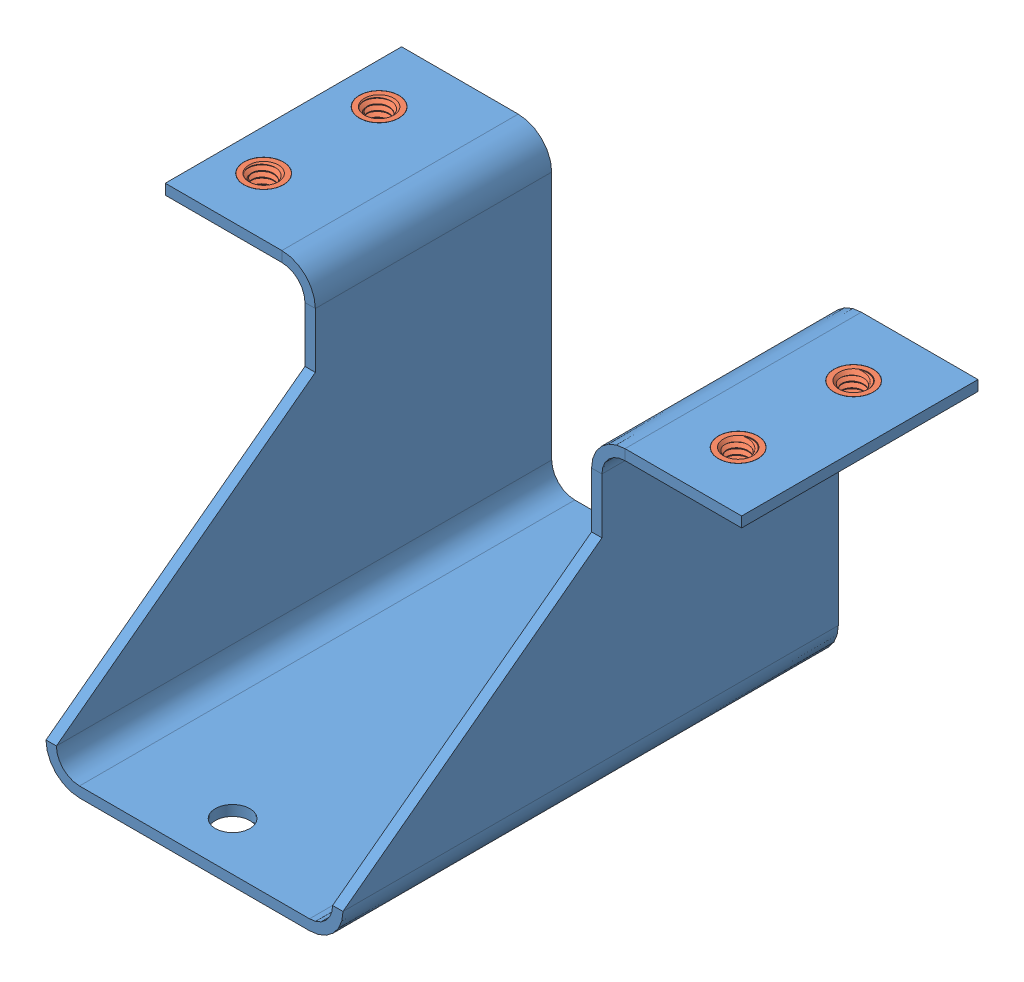
SolidWorks assembly Light Source Mount, configuration Default. Lengths in mm.
Overall size (126.81 70.06 108.97).
5 component instances, 2 part files, 4 mates.
Components (placement in the parent):
- Light Source Mount-1: Light Source Mount [Default] at origin size (126.81 69.6 108.97)
- 96439A610_18-8 SS PRESS-IN NUT FOR SHEET MTL-1: 96439A610_18-8 SS PRESS-IN NUT FOR SHEET MTL [96439A610] at (-52.197 60.706 -48.0412) x (1 0 0) z (0 -1 0) size (11.18 11.18 7.53)
- 96439A610_18-8 SS PRESS-IN NUT FOR SHEET MTL-2: 96439A610_18-8 SS PRESS-IN NUT FOR SHEET MTL [96439A610] at (-52.197 60.706 -73.4412) x (1 0 0) z (0 -1 0) size (11.18 11.18 7.53)
- 96439A610_18-8 SS PRESS-IN NUT FOR SHEET MTL-3: 96439A610_18-8 SS PRESS-IN NUT FOR SHEET MTL [96439A610] at (52.197 60.706 -73.4412) x (-1 0 0) z (0 -1 0) size (11.18 11.18 7.53)
- 96439A610_18-8 SS PRESS-IN NUT FOR SHEET MTL-4: 96439A610_18-8 SS PRESS-IN NUT FOR SHEET MTL [96439A610] at (52.197 60.706 -48.0412) x (-1 0 0) z (0 -1 0) size (11.18 11.18 7.53)
Mates (geometry in assembly coordinates):
- Coincident1: coincident anti-aligned: plane of Light Source Mount-1 through (0 65.024 0) normal (0 -1 0); plane of 96439A610_18-8 SS PRESS-IN NUT FOR SHEET MTL-1 through (-52.197 65.024 -48.0412) normal (0 1 0)
- Concentric1: concentric anti-aligned: cylinder of Light Source Mount-1 through (-52.197 -2.286 -48.0412) axis (0 1 0) radius 4.3688; cone of 96439A610_18-8 SS PRESS-IN NUT FOR SHEET MTL-1 through (-52.197 67.31 -48.0412) axis (0 -1 0)
- Concentric3: concentric anti-aligned: cylinder of Light Source Mount-1 through (-52.197 -2.286 -73.4412) axis (0 1 0) radius 4.3688; cone of 96439A610_18-8 SS PRESS-IN NUT FOR SHEET MTL-2 through (-52.197 67.31 -73.4412) axis (0 -1 0)
- Coincident2: coincident anti-aligned: plane of Light Source Mount-1 through (0 65.024 0) normal (0 -1 0); plane of 96439A610_18-8 SS PRESS-IN NUT FOR SHEET MTL-2 through (-52.197 65.024 -73.4412) normal (0 1 0)
